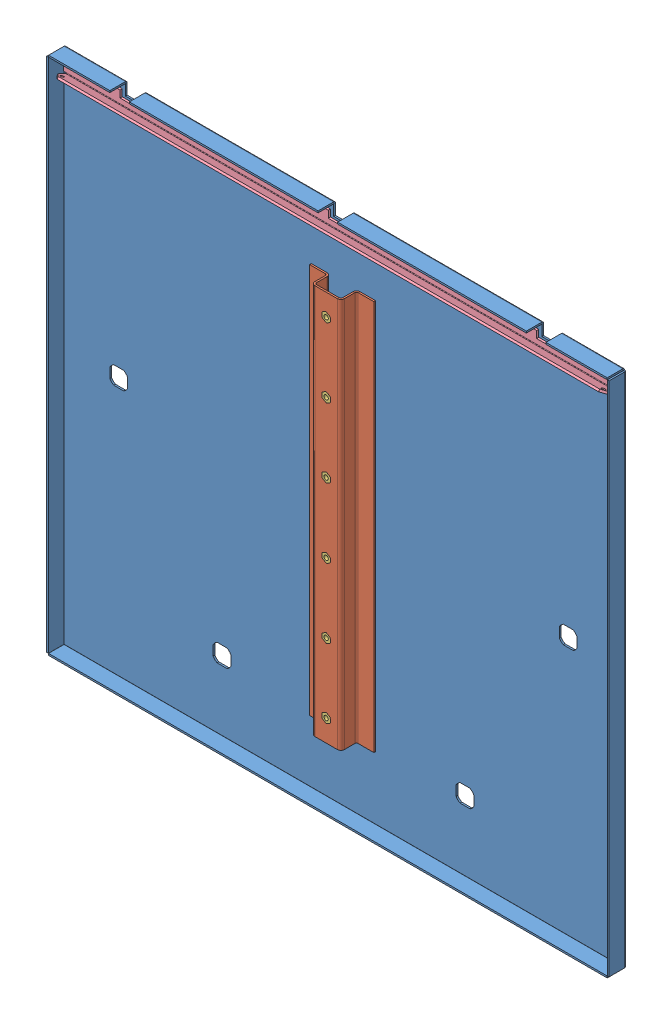
SolidWorks assembly Assemblage-PORTE-OMEGA, configuration Défaut. Lengths in mm.
Overall size (648 599 22).
10 component instances, 4 part files, 6 mates.
Components (placement in the parent):
- ENCLOSURE-PORTE-1: ENCLOSURE-PORTE [Défaut] at (-58.8958 24.4108 0) size (648 599 20)
- Assemblage-ENCLOSURE-OMEGA-1: Assemblage-ENCLOSURE-OMEGA [Défaut] at (-30.8854 309.3758 10.704) x (1 0 0) z (0 -1 0) size (74 20 450)
  - ENCLOSURE-OMEGA-PORTE-1: ENCLOSURE-OMEGA-PORTE [Défaut] at (-28.0104 18.296 0) size (74 20 450)
  - INSERTHM6X30IN-1: INSERTHM6X30IN [Défaut] at (-28.0104 8.896 484.99) size (10 12.4 10.93)
  - INSERTHM6X30IN-2: INSERTHM6X30IN [Défaut] at (-28.0104 8.896 404.98) size (10 12.4 10.93)
  - INSERTHM6X30IN-3: INSERTHM6X30IN [Défaut] at (-28.0104 8.896 324.97) size (10 12.4 10.93)
  - INSERTHM6X30IN-4: INSERTHM6X30IN [Défaut] at (-28.0104 8.896 244.96) size (10 12.4 10.93)
  - INSERTHM6X30IN-5: INSERTHM6X30IN [Défaut] at (-28.0104 8.896 164.95) size (10 12.4 10.93)
  - INSERTHM6X30IN-6: INSERTHM6X30IN [Défaut] at (-28.0104 8.896 84.94) size (10 12.4 10.93)
- EQUERRE2.5PORTE-1: EQUERRE2.5PORTE [Défaut] at (-58.8958 309.7908 2.5) x (0 1 0) z (0 0 1) size (23.7 640 17.86)
Mates (geometry in assembly coordinates):
- Coïncidente1: coincident anti-aligned: plane of ENCLOSURE-PORTE-1 through (265.1042 323.9108 0) normal (0 0 1); plane of Assemblage-ENCLOSURE-OMEGA-1/ENCLOSURE-OMEGA-PORTE-1 through (-16.8958 294.3758 0) normal (0 0 -1)
- Coïncidente2: coincident anti-aligned: plane of ENCLOSURE-PORTE-1 through (-58.8958 24.4108 0) normal (0 1 0); plane of Assemblage-ENCLOSURE-OMEGA-1/ENCLOSURE-OMEGA-PORTE-1 through (-58.8958 24.4108 29) normal (0 -1 0)
- Coïncidente3: coincident aligned: plane of ENCLOSURE-PORTE-1 through (-58.8958 24.4108 0) normal (1 0 0); plane of Assemblage-ENCLOSURE-OMEGA-1/ENCLOSURE-OMEGA-PORTE-1
- Coïncidente4: coincident anti-aligned: plane of ENCLOSURE-PORTE-1 through (265.1042 323.9108 0) normal (0 0 1); plane of EQUERRE2.5PORTE-1 through (-380.8958 321.9108 0) normal (0 0 -1)
- Coïncidente5: coincident anti-aligned: plane of ENCLOSURE-PORTE-1 through (-382.8958 321.9108 0) normal (0 -1 0); plane of EQUERRE2.5PORTE-1 through (259.1042 321.9108 0) normal (0 1 0)
- Distance1: distance = 2 mm anti-aligned: plane of ENCLOSURE-PORTE-1 through (-380.8958 323.9108 18) normal (1 0 0); plane of EQUERRE2.5PORTE-1 through (-378.8958 297.6708 0) normal (-1 0 0)
